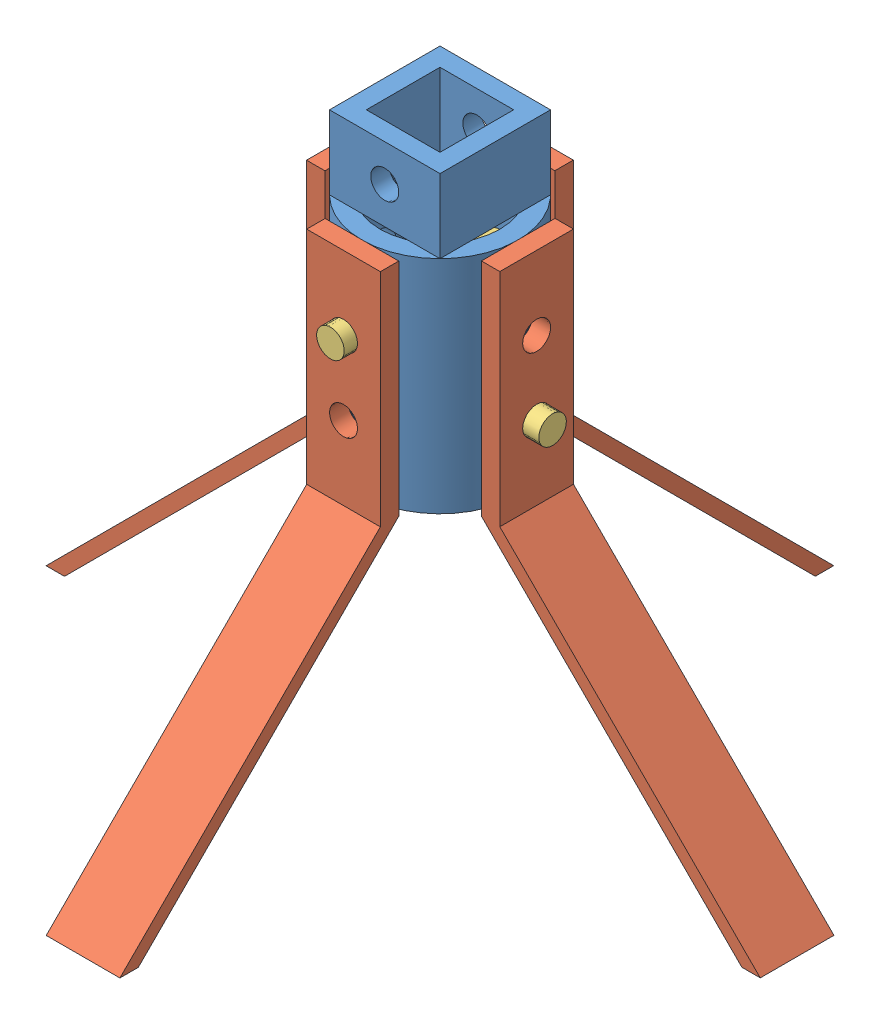
SolidWorks assembly StandBottomLegAssembly, configuration Default. Lengths in mm.
Overall size (246.19 191.32 246.19).
7 component instances, 3 part files, 5 mates.
Components (placement in the parent):
- StandBottomLegConnector-1: StandBottomLegConnector [Default] at (32.1953 86.4025 75.5871) size (53.88 101.6 53.88)
- StandBottomLeg-2: StandBottomLeg [Default] at (19.5241 10.2825 105.7028) x (0 0 -1) z (1 0 0) size (96.15 166 25.4)
- StandBottomLeg-3: StandBottomLeg [Default] at (2.0795 10.2825 62.9159) size (96.15 166 25.4)
- StandBottomLeg-4: StandBottomLeg [Default] at (44.8665 10.2825 45.4713) x (0 0 1) z (-1 0 0) size (96.15 166 25.4)
- StandBottomLeg-5: StandBottomLeg [Default] at (62.3111 10.2825 88.2582) x (-1 0 0) z (0 0 -1) size (96.15 166 25.4)
- 38inPin-1: 38inPin [Default] at (32.2241 61.0825 37.1976) x (0.99296 0.118452 0) z (0 0 1) size (9.53 9.53 76.2)
- 38inPin-2: 38inPin [Default] at (70.9806 35.6825 75.5582) x (0 0.820648 0.571435) z (-1 0 0) size (9.53 9.53 76.2)
Mates (geometry in assembly coordinates):
- Parallel4: parallel aligned: plane of StandBottomLegConnector-1 through (32.1953 86.4025 75.5871) normal (0 1 0); plane of StandBottomLeg-2 through (44.9241 86.4825 105.7028) normal (0 1 0)
- Tangent11: tangent anti-aligned: cylinder of StandBottomLegConnector-1 through (32.1953 10.2025 75.5871) axis (0 1 0) radius 26.9408; plane of StandBottomLeg-2 through (44.9241 10.2825 102.5278) normal (0 0 -1)
- Parallel7: parallel aligned: line of StandBottomLegConnector-1 through (13.1453 111.8025 94.6371) axis (0 0 -1); line of StandBottomLeg-2 through (19.5241 86.4825 108.8778) axis (0 0 -1)
- Concentric2: concentric aligned: circle of StandBottomLeg-2; circle of 38inPin-1
- Concentric3: concentric anti-aligned: circle of StandBottomLeg-5; circle of 38inPin-2
